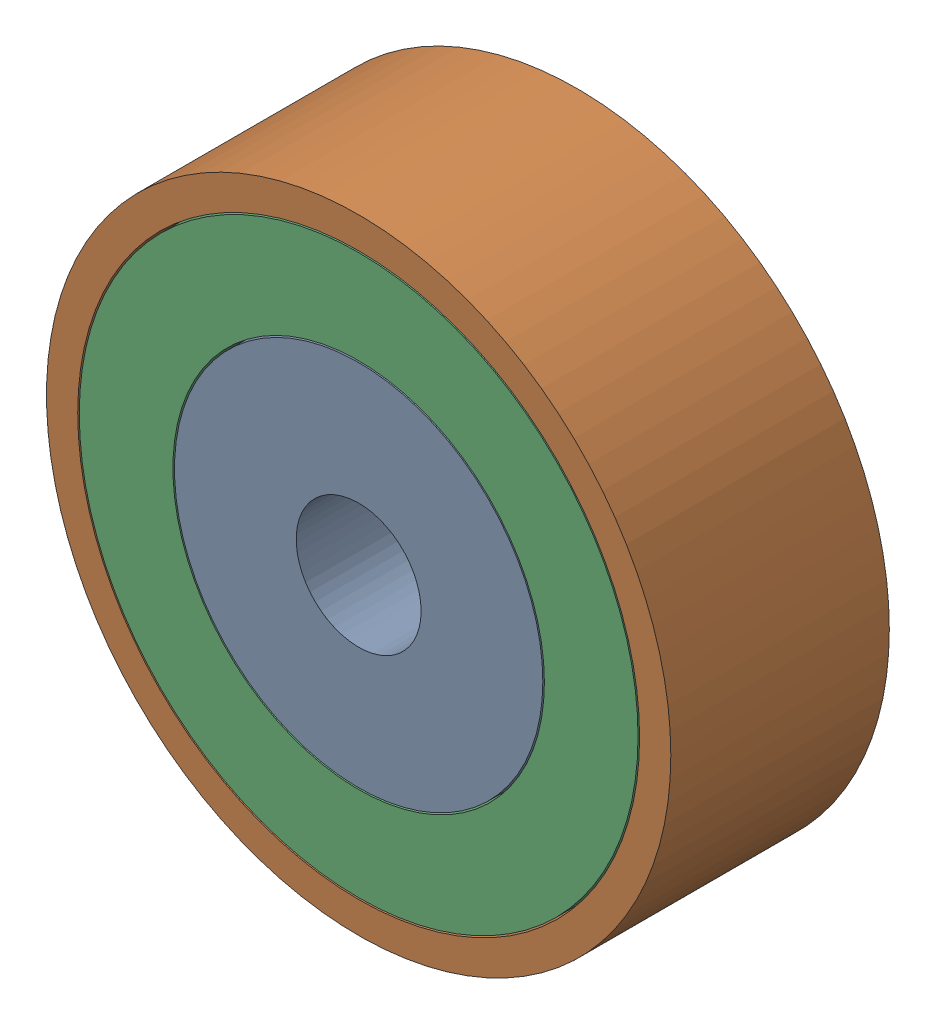
SolidWorks assembly 镜向轴承6, configuration 默认. Lengths in mm.
Overall size (20 20 7).
3 component instances, 3 part files, 4 mates.
Components (placement in the parent):
- 镜向轴承内圈-1: 镜向轴承内圈 [默认] at (-5.0655 0.8032 -6.5) size (11.8 11.8 7)
- 镜向轴承外圈-1: 镜向轴承外圈 [默认] at (-5.0655 0.8032 -6.5) size (20 20 7)
- 镜向轴承中圈-1: 镜向轴承中圈 [默认] at (-5.0655 0.8032 -6.5) size (17.9 17.9 7)
Mates (geometry in assembly coordinates):
- 重合1: coincident: plane of ? through (-5.0655 0.8032 -13.5) normal (0 0 -1); plane of ? through (-5.0655 0.8032 -13.5) normal (0 0 -1)
- 重合2: coincident: plane of ? through (-5.0655 0.8032 -13.5) normal (0 0 -1); plane of ? through (-5.0655 0.8032 -13.5) normal (0 0 -1)
- 同心1: concentric: cylinder of ? through (-5.0655 0.8032 -13.5) axis (0 0 1) radius 9; cylinder of ? through (-5.0655 0.8032 -13.5) axis (0 0 1) radius 8.95
- 同心2: concentric: cylinder of ? through (-5.0655 0.8032 -13.5) axis (0 0 1) radius 5.9; cylinder of ? through (-5.0655 0.8032 -13.5) axis (0 0 1) radius 5.95
